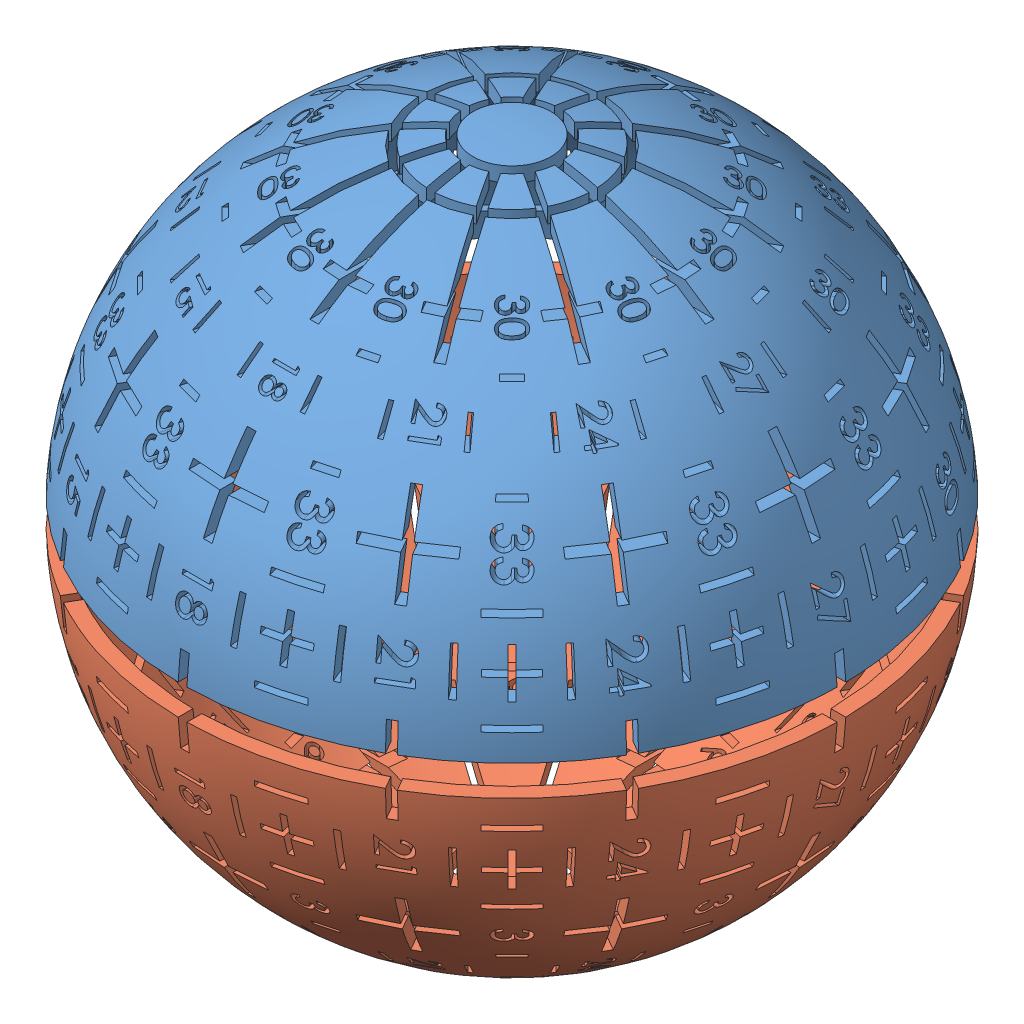
SolidWorks assembly Colored_Balls, configuration Default. Lengths in mm.
Overall size (277.79 88.9 277.79).
2 component instances, 2 part files, 3 mates.
Components (placement in the parent):
- BallV2_TopColored-1: BallV2_TopColored [Default] at (-21.5448 -32.4159 17.5791) size (88.79 42.35 88.79)
- BallV2_BottomColored-1: BallV2_BottomColored [Default] at (-21.5448 -32.3159 17.5791) x (0.5 0 -0.866025) z (-0.866025 0 -0.5) size (88.79 42.35 88.79)
Mates (geometry in assembly coordinates):
- Concentric1: concentric: circle of BallV2_TopColored-1; circle of BallV2_BottomColored-1
- Distance2: distance = 4.1 mm: plane of BallV2_BottomColored-1 through (-21.5448 -34.4159 17.5791) normal (0 1 0); plane of BallV2_TopColored-1 through (-21.5448 -30.3159 17.5791) normal (0 -1 0)
- Coincident4: coincident: plane of BallV2_TopColored-1 through (17.2435 -26.5639 -4.1377) normal (-0.5 0 -0.866025); plane of BallV2_BottomColored-1 through (17.2435 -38.1678 -4.1377) normal (-0.5 0 -0.866025)
